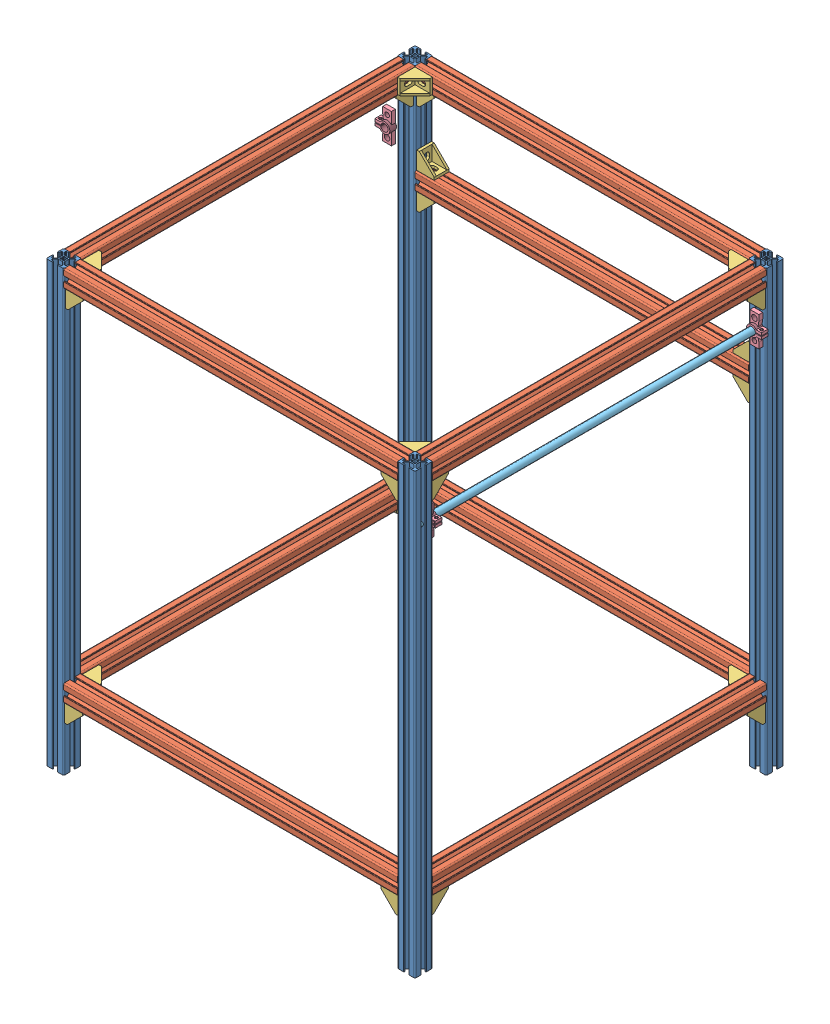
SolidWorks assembly Main_Assembly, configuration Default. Lengths in mm.
Overall size (440.32 500 420).
45 component instances, 5 part files, 130 mates.
Components (placement in the parent):
- 500_2020-1: 500_2020 [Default] at (-313.8811 597.0989 600.0008) x (1 0 0) z (0 -1 0) size (20 20 500)
- 500_2020-2: 500_2020 [Default] at (86.1189 597.0989 600.0008) x (1 0 0) z (0 -1 0) size (20 20 500)
- 500_2020-3: 500_2020 [Default] at (86.1189 597.0989 1000.0008) x (1 0 0) z (0 -1 0) size (20 20 500)
- 500_2020-4: 500_2020 [Default] at (-313.8811 597.0989 1000.0008) x (1 0 0) z (0 -1 0) size (20 20 500)
- 380_2020-1: 380_2020 [Default] at (61.5946 590.0699 1011.5541) x (0 0 1) z (-1 0 0) size (20 20 380)
- 380_2020-2: 380_2020 [Default] at (-318.4054 486.1495 582.5055) x (0 0 -1) z (1 0 0) size (20 20 380)
- 380_2020-3: 380_2020 [Default] at (-313.8811 590.0699 607.0298) size (20 20 380)
- 380_2020-4: 380_2020 [Default] at (86.1189 590.0699 607.0298) size (20 20 380)
- 380_2020-5: 380_2020 [Default] at (-318.4054 181.2813 582.5055) x (0 0 -1) z (1 0 0) size (20 20 380)
- 380_2020-6: 380_2020 [Default] at (-318.4054 572.5746 594.0587) x (0 -1 0) z (1 0 0) size (20 20 380)
- 380_2020-7: 380_2020 [Default] at (86.1189 181.2813 607.0298) size (20 20 380)
- 380_2020-8: 380_2020 [Default] at (-318.4054 181.2813 982.5055) x (0 0 -1) z (1 0 0) size (20 20 380)
- 380_2020-9: 380_2020 [Default] at (-313.8811 181.2813 607.0298) size (20 20 380)
- L CORNER-1: L CORNER [Default] at (-328.7754 577.0989 607.0298) size (17 21 21)
- L CORNER-2: L CORNER [Default] at (71.9646 577.0989 607.0298) size (17 21 21)
- L CORNER-3: L CORNER [Default] at (61.5946 577.0989 597.3998) x (0 0 1) z (-1 0 0) size (17 21 21)
- L CORNER-4: L CORNER [Default] at (-318.4054 577.0989 596.6598) x (0 0 -1) z (1 0 0) size (17 21 21)
- L CORNER-5: L CORNER [Default] at (-318.4054 577.0989 996.6598) x (0 0 -1) z (1 0 0) size (17 21 21)
- L CORNER-6: L CORNER [Default] at (61.5946 577.0989 997.3998) x (0 0 1) z (-1 0 0) size (17 21 21)
- L CORNER-7: L CORNER [Default] at (-328.7754 577.0989 987.0298) x (-1 0 0) z (0 0 -1) size (17 21 21)
- L CORNER-8: L CORNER [Default] at (71.2246 577.0989 987.0298) x (-1 0 0) z (0 0 -1) size (17 21 21)
- L CORNER-25: L CORNER [Default] at (-318.4054 587.4689 607.0298) x (0 1 0) z (0 0 1) size (17 21 21)
- L CORNER-26: L CORNER [Default] at (61.5946 587.4689 607.0298) x (0 1 0) z (-1 0 0) size (17 21 21)
- L CORNER-27: L CORNER [Default] at (-318.4054 586.7289 987.0298) x (0 1 0) z (1 0 0) size (17 21 21)
- L CORNER-28: L CORNER [Default] at (61.5946 586.7289 987.0298) x (0 1 0) z (0 0 -1) size (17 21 21)
- L CORNER-29: L CORNER [Default] at (-318.4054 473.1785 596.6598) x (0 0 -1) z (1 0 0) size (17 21 21)
- L CORNER-30: L CORNER [Default] at (61.5946 473.1785 596.6598) x (0 0 1) z (-1 0 0) size (17 21 21)
- L CORNER-31: L CORNER [Default] at (-318.4054 493.1785 596.6598) x (0 0 -1) z (0 1 0) size (17 21 21)
- L CORNER-32: L CORNER [Default] at (61.5946 493.1785 596.6598) x (0 0 -1) z (-1 0 0) size (17 21 21)
- L CORNER-33: L CORNER [Default] at (-328.0354 168.3102 607.0298) size (17 21 21)
- L CORNER-34: L CORNER [Default] at (71.9646 168.3102 607.0298) size (17 21 21)
- L CORNER-35: L CORNER [Default] at (71.2246 168.3102 987.0298) x (-1 0 0) z (0 0 -1) size (17 21 21)
- L CORNER-36: L CORNER [Default] at (-328.0354 168.3102 987.0298) x (-1 0 0) z (0 0 -1) size (17 21 21)
- L CORNER-37: L CORNER [Default] at (61.5946 168.3102 596.6598) x (0 0 1) z (-1 0 0) size (17 21 21)
- L CORNER-38: L CORNER [Default] at (61.5946 168.3102 997.3998) x (0 0 1) z (-1 0 0) size (17 21 21)
- L CORNER-39: L CORNER [Default] at (-318.4054 168.3102 997.3998) x (0 0 -1) z (1 0 0) size (17 21 21)
- L CORNER-40: L CORNER [Default] at (-318.4054 168.3102 597.3998) x (0 0 -1) z (1 0 0) size (17 21 21)
- L CORNER-41: L CORNER [Default] at (61.5946 177.9402 987.0298) x (0 -1 0) z (-1 0 0) size (17 21 21)
- L CORNER-42: L CORNER [Default] at (61.5946 177.9402 607.0298) x (0 1 0) z (-1 0 0) size (17 21 21)
- L CORNER-43: L CORNER [Default] at (-318.4054 177.9402 987.0298) x (0 -1 0) z (0 0 -1) size (17 21 21)
- L CORNER-44: L CORNER [Default] at (-318.4054 177.9402 607.0298) x (0 1 0) z (0 0 1) size (17 21 21)
- Y_Shaft_Clamp-1: Y_Shaft_Clamp [Default] at (-345.2075 526.6815 607.0298) x (0 1 0) z (0 0 1) size (34 17.1 8)
- Y_Shaft_Clamp-2: Y_Shaft_Clamp [Default] at (73.1078 535.5438 607.0298) x (0 -1 0) z (0 0 1) size (34 17.1 8)
- Y_Shaft_Clamp-3: Y_Shaft_Clamp [Default] at (73.1078 535.5438 987.0298) x (0 1 0) z (0 0 -1) size (34 17.1 8)
- Rod_400-1: Rod_400 [Default] at (72.9646 535.5076 1000.6848) x (0.610769 -0.791809 0) z (0.791809 0.610769 0) size (8 400 8)
Mates (geometry in assembly coordinates):
- Coincident2: coincident anti-aligned: plane of 500_2020-1 through (-331.5434 97.0989 607.0298) normal (0 0 1); plane of 380_2020-3 through (-318.9134 590.2369 607.0298) normal (0 0 -1)
- Coincident3: coincident aligned: plane of 500_2020-1 through (-318.4054 97.0989 600.1678) normal (1 0 0); plane of 380_2020-3 through (-318.4054 590.2369 987.0298) normal (1 0 0)
- Coincident4: coincident aligned: plane of 500_2020-1 through (-318.9134 597.0989 600.1678) normal (0 1 0); plane of 380_2020-3 through (-325.2674 597.0989 987.0298) normal (0 1 0)
- Coincident5: coincident anti-aligned: plane of 500_2020-1 through (-318.4054 97.0989 600.1678) normal (1 0 0); plane of 380_2020-6 through (-318.4054 577.6069 593.8918) normal (-1 0 0)
- Coincident6: coincident aligned: plane of 500_2020-1 through (-325.2674 97.0989 587.0298) normal (0 0 -1); plane of 380_2020-6 through (61.5946 590.2369 587.0298) normal (0 0 -1)
- Coincident7: coincident aligned: plane of 500_2020-1 through (-318.9134 597.0989 600.1678) normal (0 1 0); plane of 380_2020-6 through (61.5946 597.0989 600.1678) normal (0 1 0)
- Coincident8: coincident aligned: plane of 500_2020-4 through (-318.9134 597.0989 1000.1678) normal (0 1 0); plane of 380_2020-3 through (-325.2674 597.0989 987.0298) normal (0 1 0)
- Coincident9: coincident anti-aligned: plane of 500_2020-4 through (-325.2674 97.0989 987.0298) normal (0 0 -1); plane of 380_2020-3 through (-318.9134 590.2369 987.0298) normal (0 0 1)
- Coincident10: coincident aligned: plane of 500_2020-4 through (-318.4054 97.0989 993.8918) normal (1 0 0); plane of 380_2020-3 through (-318.4054 583.9609 987.0298) normal (1 0 0)
- Coincident11: coincident aligned: plane of 500_2020-2 through (81.0866 597.0989 600.1678) normal (0 1 0); plane of 380_2020-6 through (61.5946 597.0989 600.1678) normal (0 1 0)
- Coincident12: coincident anti-aligned: plane of 500_2020-2 through (61.5946 97.0989 593.8918) normal (-1 0 0); plane of 380_2020-6 through (61.5946 577.6069 593.8918) normal (1 0 0)
- Coincident13: coincident aligned: plane of 500_2020-2 through (68.4566 97.0989 607.0298) normal (0 0 1); plane of 380_2020-6 through (61.5946 583.9609 607.0298) normal (0 0 1)
- Coincident14: coincident aligned: plane of 500_2020-2 through (81.0866 597.0989 600.1678) normal (0 1 0); plane of 380_2020-4 through (68.4566 597.0989 987.0298) normal (0 1 0)
- Coincident15: coincident anti-aligned: plane of 500_2020-2 through (74.7326 97.0989 607.0298) normal (0 0 1); plane of 380_2020-4 through (81.0866 590.2369 607.0298) normal (0 0 -1)
- Coincident16: coincident aligned: plane of 500_2020-2 through (81.5946 97.0989 600.1678) normal (1 0 0); plane of 380_2020-4 through (81.5946 583.9609 987.0298) normal (1 0 0)
- Coincident17: coincident aligned: plane of 500_2020-3 through (81.0866 597.0989 1000.1678) normal (0 1 0); plane of 380_2020-4 through (68.4566 597.0989 987.0298) normal (0 1 0)
- Coincident18: coincident anti-aligned: plane of 500_2020-3 through (74.7326 97.0989 987.0298) normal (0 0 -1); plane of 380_2020-4 through (81.0866 590.2369 987.0298) normal (0 0 1)
- Coincident19: coincident aligned: plane of 500_2020-3 through (61.5946 97.0989 993.8918) normal (-1 0 0); plane of 380_2020-4 through (61.5946 590.2369 987.0298) normal (-1 0 0)
- Coincident20: coincident aligned: plane of 500_2020-4 through (-318.9134 597.0989 1000.1678) normal (0 1 0); plane of 380_2020-1 through (-318.4054 597.0989 993.8918) normal (0 1 0)
- Coincident21: coincident anti-aligned: plane of 500_2020-4 through (-318.4054 97.0989 993.8918) normal (1 0 0); plane of 380_2020-1 through (-318.4054 590.2369 1006.5218) normal (-1 0 0)
- Coincident22: coincident aligned: plane of 500_2020-4 through (-325.2674 97.0989 1007.0298) normal (0 0 1); plane of 380_2020-1 through (-318.4054 590.2369 1007.0298) normal (0 0 1)
- Coincident23: coincident anti-aligned: plane of 500_2020-4 through (-331.5434 97.0989 987.0298) normal (0 0 -1); plane of 380_2020-9 through (-318.9134 181.4482 987.0298) normal (0 0 1)
- Coincident24: coincident aligned: plane of 500_2020-4 through (-318.4054 97.0989 993.8918) normal (1 0 0); plane of 380_2020-9 through (-318.4054 181.4482 987.0298) normal (1 0 0)
- Coincident25: coincident aligned: plane of 380_2020-7 through (68.4566 188.3102 987.0298) normal (0 1 0); plane of 380_2020-9 through (-331.5434 188.3102 987.0298) normal (0 1 0)
- Coincident26: coincident anti-aligned: plane of 500_2020-3 through (68.4566 97.0989 987.0298) normal (0 0 -1); plane of 380_2020-7 through (81.0866 181.4482 987.0298) normal (0 0 1)
- Coincident27: coincident aligned: plane of 500_2020-3 through (81.5946 97.0989 993.8918) normal (1 0 0); plane of 380_2020-7 through (81.5946 181.4482 987.0298) normal (1 0 0)
- Coincident29: coincident aligned: plane of 500_2020-3 through (74.7326 97.0989 1007.0298) normal (0 0 1); plane of 380_2020-8 through (61.5946 175.1722 1007.0298) normal (0 0 1)
- Coincident30: coincident anti-aligned: plane of 500_2020-3 through (61.5946 97.0989 993.8918) normal (-1 0 0); plane of 380_2020-8 through (61.5946 181.4482 987.5378) normal (1 0 0)
- Coincident31: coincident aligned: plane of 380_2020-8 through (61.5946 188.3102 993.8918) normal (0 1 0); plane of 380_2020-9 through (-325.2674 188.3102 987.0298) normal (0 1 0)
- Coincident32: coincident anti-aligned: plane of 500_2020-2 through (61.5946 97.0989 593.8918) normal (-1 0 0); plane of 380_2020-5 through (61.5946 181.4482 587.5378) normal (1 0 0)
- Coincident33: coincident aligned: plane of 500_2020-2 through (68.4566 97.0989 607.0298) normal (0 0 1); plane of 380_2020-5 through (61.5946 181.4482 607.0298) normal (0 0 1)
- Coincident34: coincident aligned: plane of 380_2020-5 through (61.5946 188.3102 600.1678) normal (0 1 0); plane of 380_2020-9 through (-325.2674 188.3102 987.0298) normal (0 1 0)
- Coincident35: coincident aligned: plane of 500_2020-2 through (74.7326 97.0989 607.0298) normal (0 0 1); plane of 380_2020-2 through (61.5946 480.0405 607.0298) normal (0 0 1)
- Coincident36: coincident anti-aligned: plane of 500_2020-2 through (61.5946 97.0989 593.8918) normal (-1 0 0); plane of 380_2020-2 through (61.5946 486.3165 587.5378) normal (1 0 0)
- Coincident37: coincident anti-aligned: plane of 380_2020-3 through (-331.5434 577.0989 987.0298) normal (0 -1 0); plane of L CORNER-1 through (-320.2754 577.0989 607.0298) normal (0 1 0)
- Coincident38: coincident anti-aligned: plane of 500_2020-1 through (-331.5434 97.0989 607.0298) normal (0 0 1); plane of L CORNER-1 through (-320.2754 577.0989 607.0298) normal (0 0 -1)
- Coincident39: coincident aligned: plane of 380_2020-3 through (-325.7754 577.6069 987.0298) normal (-1 0 0); plane of L CORNER-1 through (-325.7754 577.0999 616.0298) normal (-1 0 0)
- Coincident40: coincident anti-aligned: plane of 500_2020-2 through (68.4566 97.0989 607.0298) normal (0 0 1); plane of L CORNER-2 through (80.4646 577.0989 607.0298) normal (0 0 -1)
- Coincident41: coincident anti-aligned: plane of 380_2020-4 through (74.7326 577.0989 987.0298) normal (0 -1 0); plane of L CORNER-2 through (80.4646 577.0989 607.0298) normal (0 1 0)
- Coincident42: coincident aligned: plane of 380_2020-4 through (68.9646 577.6069 987.0298) normal (1 0 0); plane of L CORNER-2 through (68.9646 577.0999 616.0298) normal (1 0 0)
- Coincident43: coincident anti-aligned: plane of 500_2020-2 through (61.5946 97.0989 593.8918) normal (-1 0 0); plane of L CORNER-3 through (61.5946 577.0989 605.8998) normal (1 0 0)
- Coincident44: coincident anti-aligned: plane of 380_2020-6 through (61.5946 577.0989 593.8918) normal (0 -1 0); plane of L CORNER-3 through (61.5946 577.0989 605.8998) normal (0 1 0)
- Coincident45: coincident aligned: plane of 500_2020-2 through (62.1026 97.0989 594.3998) normal (0 0 1); plane of L CORNER-3 through (61.5956 568.0989 594.3998) normal (0 0 1)
- Coincident46: coincident anti-aligned: plane of 500_2020-1 through (-318.4054 97.0989 593.8918) normal (1 0 0); plane of L CORNER-4 through (-318.4054 577.0989 588.1598) normal (-1 0 0)
- Coincident47: coincident anti-aligned: plane of 380_2020-6 through (61.5946 577.0989 593.8918) normal (0 -1 0); plane of L CORNER-4 through (-318.4054 577.0989 588.1598) normal (0 1 0)
- Coincident48: coincident aligned: plane of 500_2020-1 through (-318.9134 97.0989 599.6598) normal (0 0 -1); plane of L CORNER-4 through (-318.4064 568.0989 599.6598) normal (0 0 -1)
- Coincident49: coincident anti-aligned: plane of 500_2020-4 through (-318.4054 97.0989 1000.1678) normal (1 0 0); plane of L CORNER-5 through (-318.4054 577.0989 988.1598) normal (-1 0 0)
- Coincident50: coincident anti-aligned: plane of 380_2020-1 through (-318.4054 577.0989 993.8918) normal (0 -1 0); plane of L CORNER-5 through (-318.4054 577.0989 988.1598) normal (0 1 0)
- Coincident51: coincident aligned: plane of 500_2020-4 through (-318.9134 97.0989 999.6598) normal (0 0 -1); plane of L CORNER-5 through (-318.4064 568.0989 999.6598) normal (0 0 -1)
- Coincident53: coincident anti-aligned: plane of 500_2020-4 through (-325.2674 97.0989 987.0298) normal (0 0 -1); plane of L CORNER-7 through (-337.2754 577.0989 987.0298) normal (0 0 1)
- Coincident54: coincident anti-aligned: plane of 380_2020-3 through (-325.2674 577.0989 987.0298) normal (0 -1 0); plane of L CORNER-7 through (-337.2754 577.0989 987.0298) normal (0 1 0)
- Coincident55: coincident aligned: plane of 500_2020-4 through (-325.7754 97.0989 987.5378) normal (-1 0 0); plane of L CORNER-7 through (-325.7754 568.0989 987.0308) normal (-1 0 0)
- Coincident56: coincident anti-aligned: plane of 500_2020-3 through (61.5946 97.0989 1000.1678) normal (-1 0 0); plane of L CORNER-6 through (61.5946 577.0989 1005.8998) normal (1 0 0)
- Coincident57: coincident anti-aligned: plane of 380_2020-1 through (-318.4054 577.0989 993.8918) normal (0 -1 0); plane of L CORNER-6 through (61.5946 577.0989 1005.8998) normal (0 1 0)
- Coincident58: coincident aligned: plane of 500_2020-3 through (62.1026 97.0989 994.3998) normal (0 0 1); plane of L CORNER-6 through (61.5956 568.0989 994.3998) normal (0 0 1)
- Coincident59: coincident anti-aligned: plane of 380_2020-4 through (74.7326 577.0989 987.0298) normal (0 -1 0); plane of L CORNER-8 through (62.7246 577.0989 987.0298) normal (0 1 0)
- Coincident60: coincident anti-aligned: plane of 500_2020-3 through (68.4566 97.0989 987.0298) normal (0 0 -1); plane of L CORNER-8 through (62.7246 577.0989 987.0298) normal (0 0 1)
- Coincident61: coincident aligned: plane of 500_2020-3 through (74.2246 97.0989 987.5378) normal (-1 0 0); plane of L CORNER-8 through (74.2246 568.0989 987.0308) normal (-1 0 0)
- Coincident62: coincident anti-aligned: plane of 380_2020-6 through (61.5946 590.2369 607.0298) normal (0 0 1); plane of L CORNER-25 through (-318.4054 595.9689 607.0298) normal (0 0 -1)
- Coincident63: coincident anti-aligned: plane of 380_2020-3 through (-318.4054 590.2369 987.0298) normal (1 0 0); plane of L CORNER-25 through (-318.4054 595.9689 607.0298) normal (-1 0 0)
- Coincident64: coincident aligned: plane of 380_2020-6 through (61.5946 584.4689 606.5218) normal (0 1 0); plane of L CORNER-25 through (-309.4054 584.4689 607.0288) normal (0 1 0)
- Coincident65: coincident anti-aligned: plane of 380_2020-4 through (61.5946 590.2369 987.0298) normal (-1 0 0); plane of L CORNER-26 through (61.5946 595.9689 607.0298) normal (1 0 0)
- Coincident66: coincident anti-aligned: plane of 380_2020-6 through (61.5946 583.9609 607.0298) normal (0 0 1); plane of L CORNER-26 through (61.5946 595.9689 607.0298) normal (0 0 -1)
- Coincident67: coincident aligned: plane of 380_2020-4 through (62.1026 584.4689 987.0298) normal (0 1 0); plane of L CORNER-26 through (61.5956 584.4689 616.0298) normal (0 1 0)
- Coincident68: coincident anti-aligned: plane of 380_2020-3 through (-318.4054 590.2369 987.0298) normal (1 0 0); plane of L CORNER-27 through (-318.4054 595.2289 987.0298) normal (-1 0 0)
- Coincident69: coincident anti-aligned: plane of 380_2020-1 through (-318.4054 590.2369 987.0298) normal (0 0 -1); plane of L CORNER-27 through (-318.4054 595.2289 987.0298) normal (0 0 1)
- Coincident70: coincident aligned: plane of 380_2020-3 through (-318.9134 589.7289 987.0298) normal (0 -1 0); plane of L CORNER-27 through (-318.4064 589.7289 978.0298) normal (0 -1 0)
- Coincident71: coincident anti-aligned: plane of 380_2020-1 through (-318.4054 583.9609 987.0298) normal (0 0 -1); plane of L CORNER-28 through (61.5946 595.2289 987.0298) normal (0 0 1)
- Coincident72: coincident anti-aligned: plane of 380_2020-4 through (61.5946 590.2369 987.0298) normal (-1 0 0); plane of L CORNER-28 through (61.5946 595.2289 987.0298) normal (1 0 0)
- Coincident73: coincident aligned: plane of 380_2020-4 through (62.1026 589.7289 987.0298) normal (0 -1 0); plane of L CORNER-28 through (61.5956 589.7289 978.0298) normal (0 -1 0)
- Coincident74: coincident anti-aligned: plane of 380_2020-2 through (61.5946 473.1785 600.1678) normal (0 -1 0); plane of L CORNER-29 through (-318.4054 473.1785 588.1598) normal (0 1 0)
- Coincident75: coincident anti-aligned: plane of 500_2020-1 through (-318.4054 97.0989 600.1678) normal (1 0 0); plane of L CORNER-29 through (-318.4054 473.1785 588.1598) normal (-1 0 0)
- Coincident76: coincident aligned: plane of 500_2020-1 through (-318.9134 97.0989 599.6598) normal (0 0 -1); plane of L CORNER-29 through (-318.4064 464.1785 599.6598) normal (0 0 -1)
- Coincident77: coincident anti-aligned: plane of 380_2020-2 through (61.5946 473.1785 600.1678) normal (0 -1 0); plane of L CORNER-30 through (61.5946 473.1785 605.1598) normal (0 1 0)
- Coincident78: coincident anti-aligned: plane of 500_2020-2 through (61.5946 97.0989 593.8918) normal (-1 0 0); plane of L CORNER-30 through (61.5946 473.1785 605.1598) normal (1 0 0)
- Coincident79: coincident aligned: plane of 500_2020-2 through (62.1026 97.0989 599.6598) normal (0 0 -1); plane of L CORNER-30 through (61.5956 464.1785 599.6598) normal (0 0 -1)
- Coincident80: coincident anti-aligned: plane of 500_2020-1 through (-318.4054 97.0989 600.1678) normal (1 0 0); plane of L CORNER-31 through (-318.4054 493.1785 588.1598) normal (-1 0 0)
- Coincident81: coincident anti-aligned: plane of 380_2020-2 through (61.5946 493.1785 593.8918) normal (0 1 0); plane of L CORNER-31 through (-318.4054 493.1785 588.1598) normal (0 -1 0)
- Coincident82: coincident aligned: plane of 380_2020-2 through (61.5946 492.6705 599.6598) normal (0 0 -1); plane of L CORNER-31 through (-309.4054 493.1775 599.6598) normal (0 0 -1)
- Coincident83: coincident anti-aligned: plane of 500_2020-2 through (61.5946 97.0989 593.8918) normal (-1 0 0); plane of L CORNER-32 through (61.5946 493.1785 588.1598) normal (1 0 0)
- Coincident84: coincident anti-aligned: plane of 380_2020-2 through (61.5946 493.1785 593.8918) normal (0 1 0); plane of L CORNER-32 through (61.5946 493.1785 588.1598) normal (0 -1 0)
- Coincident85: coincident aligned: plane of 380_2020-2 through (61.5946 492.6705 599.6598) normal (0 0 -1); plane of L CORNER-32 through (52.5946 493.1775 599.6598) normal (0 0 -1)
- Coincident86: coincident anti-aligned: plane of 500_2020-1 through (-331.5434 97.0989 607.0298) normal (0 0 1); plane of L CORNER-33 through (-319.5354 168.3102 607.0298) normal (0 0 -1)
- Coincident88: coincident anti-aligned: plane of 380_2020-9 through (-325.2674 168.3102 987.0298) normal (0 -1 0); plane of L CORNER-33 through (-319.5354 168.3102 607.0298) normal (0 1 0)
- Coincident89: coincident aligned: plane of 380_2020-9 through (-331.0354 168.8182 987.0298) normal (1 0 0); plane of L CORNER-33 through (-331.0354 168.3112 616.0298) normal (1 0 0)
- Coincident90: coincident anti-aligned: plane of 380_2020-7 through (68.4566 168.3102 987.0298) normal (0 -1 0); plane of L CORNER-34 through (80.4646 168.3102 607.0298) normal (0 1 0)
- Coincident91: coincident anti-aligned: plane of 500_2020-2 through (68.4566 97.0989 607.0298) normal (0 0 1); plane of L CORNER-34 through (80.4646 168.3102 607.0298) normal (0 0 -1)
- Coincident92: coincident aligned: plane of 500_2020-2 through (68.9646 97.0989 606.5218) normal (1 0 0); plane of L CORNER-34 through (68.9646 159.3102 607.0288) normal (1 0 0)
- Coincident93: coincident anti-aligned: plane of 500_2020-3 through (68.4566 97.0989 987.0298) normal (0 0 -1); plane of L CORNER-35 through (62.7246 168.3102 987.0298) normal (0 0 1)
- Coincident94: coincident anti-aligned: plane of 380_2020-7 through (74.7326 168.3102 987.0298) normal (0 -1 0); plane of L CORNER-35 through (62.7246 168.3102 987.0298) normal (0 1 0)
- Coincident95: coincident aligned: plane of 380_2020-7 through (74.2246 168.8182 987.0298) normal (-1 0 0); plane of L CORNER-35 through (74.2246 168.3112 978.0298) normal (-1 0 0)
- Coincident96: coincident anti-aligned: plane of 500_2020-4 through (-325.2674 97.0989 987.0298) normal (0 0 -1); plane of L CORNER-36 through (-336.5354 168.3102 987.0298) normal (0 0 1)
- Coincident97: coincident anti-aligned: plane of 380_2020-9 through (-325.2674 168.3102 987.0298) normal (0 -1 0); plane of L CORNER-36 through (-336.5354 168.3102 987.0298) normal (0 1 0)
- Coincident98: coincident aligned: plane of 380_2020-9 through (-331.0354 168.8182 987.0298) normal (1 0 0); plane of L CORNER-36 through (-331.0354 168.3112 978.0298) normal (1 0 0)
- Coincident99: coincident anti-aligned: plane of 500_2020-4 through (-318.4054 97.0989 993.8918) normal (1 0 0); plane of L CORNER-39 through (-318.4054 168.3102 988.8998) normal (-1 0 0)
- Coincident100: coincident anti-aligned: plane of 380_2020-8 through (61.5946 168.3102 993.8918) normal (0 -1 0); plane of L CORNER-39 through (-318.4054 168.3102 988.8998) normal (0 1 0)
- Coincident101: coincident aligned: plane of 500_2020-4 through (-318.9134 97.0989 994.3998) normal (0 0 1); plane of L CORNER-39 through (-318.4064 159.3102 994.3998) normal (0 0 1)
- Coincident102: coincident anti-aligned: plane of 500_2020-1 through (-318.4054 97.0989 593.8918) normal (1 0 0); plane of L CORNER-40 through (-318.4054 168.3102 588.8998) normal (-1 0 0)
- Coincident103: coincident anti-aligned: plane of 380_2020-5 through (61.5946 168.3102 600.1678) normal (0 -1 0); plane of L CORNER-40 through (-318.4054 168.3102 588.8998) normal (0 1 0)
- Coincident104: coincident aligned: plane of 380_2020-5 through (61.5946 168.8182 594.3998) normal (0 0 1); plane of L CORNER-40 through (-309.4054 168.3112 594.3998) normal (0 0 1)
- Coincident105: coincident anti-aligned: plane of 500_2020-2 through (61.5946 97.0989 600.1678) normal (-1 0 0); plane of L CORNER-37 through (61.5946 168.3102 605.1598) normal (1 0 0)
- Coincident106: coincident anti-aligned: plane of 380_2020-5 through (61.5946 168.3102 600.1678) normal (0 -1 0); plane of L CORNER-37 through (61.5946 168.3102 605.1598) normal (0 1 0)
- Coincident107: coincident aligned: plane of 380_2020-5 through (61.5946 168.8182 599.6598) normal (0 0 -1); plane of L CORNER-37 through (52.5946 168.3112 599.6598) normal (0 0 -1)
- Coincident108: coincident anti-aligned: plane of 500_2020-3 through (61.5946 97.0989 993.8918) normal (-1 0 0); plane of L CORNER-38 through (61.5946 168.3102 1005.8998) normal (1 0 0)
- Coincident109: coincident anti-aligned: plane of 380_2020-8 through (61.5946 168.3102 1000.1678) normal (0 -1 0); plane of L CORNER-38 through (61.5946 168.3102 1005.8998) normal (0 1 0)
- Coincident110: coincident aligned: plane of 380_2020-8 through (61.5946 168.8182 994.3998) normal (0 0 1); plane of L CORNER-38 through (52.5946 168.3112 994.3998) normal (0 0 1)
- Coincident111: coincident anti-aligned: plane of 380_2020-9 through (-318.4054 175.1722 987.0298) normal (1 0 0); plane of L CORNER-44 through (-318.4054 186.4402 607.0298) normal (-1 0 0)
- Coincident112: coincident anti-aligned: plane of 380_2020-5 through (61.5946 175.1722 607.0298) normal (0 0 1); plane of L CORNER-44 through (-318.4054 186.4402 607.0298) normal (0 0 -1)
- Coincident113: coincident aligned: plane of 380_2020-5 through (61.5946 180.9402 606.5218) normal (0 -1 0); plane of L CORNER-44 through (-309.4054 180.9402 607.0288) normal (0 -1 0)
- Coincident114: coincident anti-aligned: plane of 380_2020-8 through (61.5946 175.1722 987.0298) normal (0 0 -1); plane of L CORNER-43 through (-318.4054 169.4402 987.0298) normal (0 0 1)
- Coincident115: coincident anti-aligned: plane of 380_2020-9 through (-318.4054 181.4482 987.0298) normal (1 0 0); plane of L CORNER-43 through (-318.4054 169.4402 987.0298) normal (-1 0 0)
- Coincident116: coincident aligned: plane of 380_2020-9 through (-318.9134 180.9402 987.0298) normal (0 -1 0); plane of L CORNER-43 through (-318.4064 180.9402 978.0298) normal (0 -1 0)
- Coincident117: coincident anti-aligned: plane of 380_2020-7 through (61.5946 175.1722 987.0298) normal (-1 0 0); plane of L CORNER-41 through (61.5946 169.4402 987.0298) normal (1 0 0)
- Coincident118: coincident anti-aligned: plane of 380_2020-8 through (61.5946 175.1722 987.0298) normal (0 0 -1); plane of L CORNER-41 through (61.5946 169.4402 987.0298) normal (0 0 1)
- Coincident119: coincident aligned: plane of 380_2020-8 through (61.5946 180.9402 987.5378) normal (0 -1 0); plane of L CORNER-41 through (52.5946 180.9402 987.0308) normal (0 -1 0)
- Coincident120: coincident anti-aligned: plane of 380_2020-5 through (61.5946 175.1722 607.0298) normal (0 0 1); plane of L CORNER-42 through (61.5946 186.4402 607.0298) normal (0 0 -1)
- Coincident121: coincident anti-aligned: plane of 380_2020-7 through (61.5946 181.4482 987.0298) normal (-1 0 0); plane of L CORNER-42 through (61.5946 186.4402 607.0298) normal (1 0 0)
- Coincident122: coincident aligned: plane of 380_2020-7 through (62.1026 180.9402 987.0298) normal (0 -1 0); plane of L CORNER-42 through (61.5956 180.9402 616.0298) normal (0 -1 0)
- Parallel1: parallel aligned: plane of 500_2020-1 through (-318.4054 97.0989 600.1678) normal (1 0 0); plane of Y_Shaft_Clamp-1 through (-340.2075 526.6815 607.0298) normal (1 0 0)
- Coincident124: coincident anti-aligned: plane of 500_2020-1 through (-325.2674 97.0989 607.0298) normal (0 0 1); plane of Y_Shaft_Clamp-1 through (-345.2075 526.6815 607.0298) normal (0 0 -1)
- Parallel3: parallel aligned: plane of 500_2020-2 through (61.5946 97.0989 600.1678) normal (-1 0 0); plane of Y_Shaft_Clamp-2 through (68.1078 535.5438 607.0298) normal (-1 0 0)
- Coincident129: coincident anti-aligned: plane of 500_2020-2 through (74.7326 97.0989 607.0298) normal (0 0 1); plane of Y_Shaft_Clamp-2 through (73.1078 535.5438 607.0298) normal (0 0 -1)
- Coincident130: coincident anti-aligned: plane of 500_2020-3 through (74.7326 97.0989 987.0298) normal (0 0 -1); plane of Y_Shaft_Clamp-3 through (73.1078 535.5438 987.0298) normal (0 0 1)
- Parallel4: parallel aligned: plane of 500_2020-3 through (61.5946 97.0989 993.8918) normal (-1 0 0); plane of Y_Shaft_Clamp-3 through (68.1078 535.5438 987.0298) normal (-1 0 0)
- Coincident132: coincident aligned: plane of Y_Shaft_Clamp-2 through (84.1078 535.5438 607.0298) normal (1 0 0); plane of Y_Shaft_Clamp-3 through (84.1078 535.5438 987.0298) normal (1 0 0)
- Coincident133: coincident aligned: plane of Y_Shaft_Clamp-2 through (73.1078 532.0438 607.0298) normal (0 -1 0); plane of Y_Shaft_Clamp-3 through (73.1078 532.0438 987.0298) normal (0 -1 0)
- Coincident134: coincident: point of Y_Shaft_Clamp-3; cylinder of Rod_400-1 through (72.9646 535.5076 600.6848) axis (0 0 1) radius 4
- Coincident140: coincident: point of Y_Shaft_Clamp-3; cylinder of Rod_400-1 through (72.9646 535.5076 600.6848) axis (0 0 1) radius 4
- Coincident147: coincident anti-aligned: plane of 500_2020-2 through (73.9785 97.0989 600.6848) normal (0 0 1); plane of Rod_400-1 through (72.9646 535.5076 600.6848) normal (0 0 -1)
- Tangent2: tangent anti-aligned: plane of 500_2020-2 through (68.9646 97.0989 606.5218) normal (1 0 0); cylinder of Rod_400-1 through (72.9646 535.5076 600.6848) axis (0 0 1) radius 4
